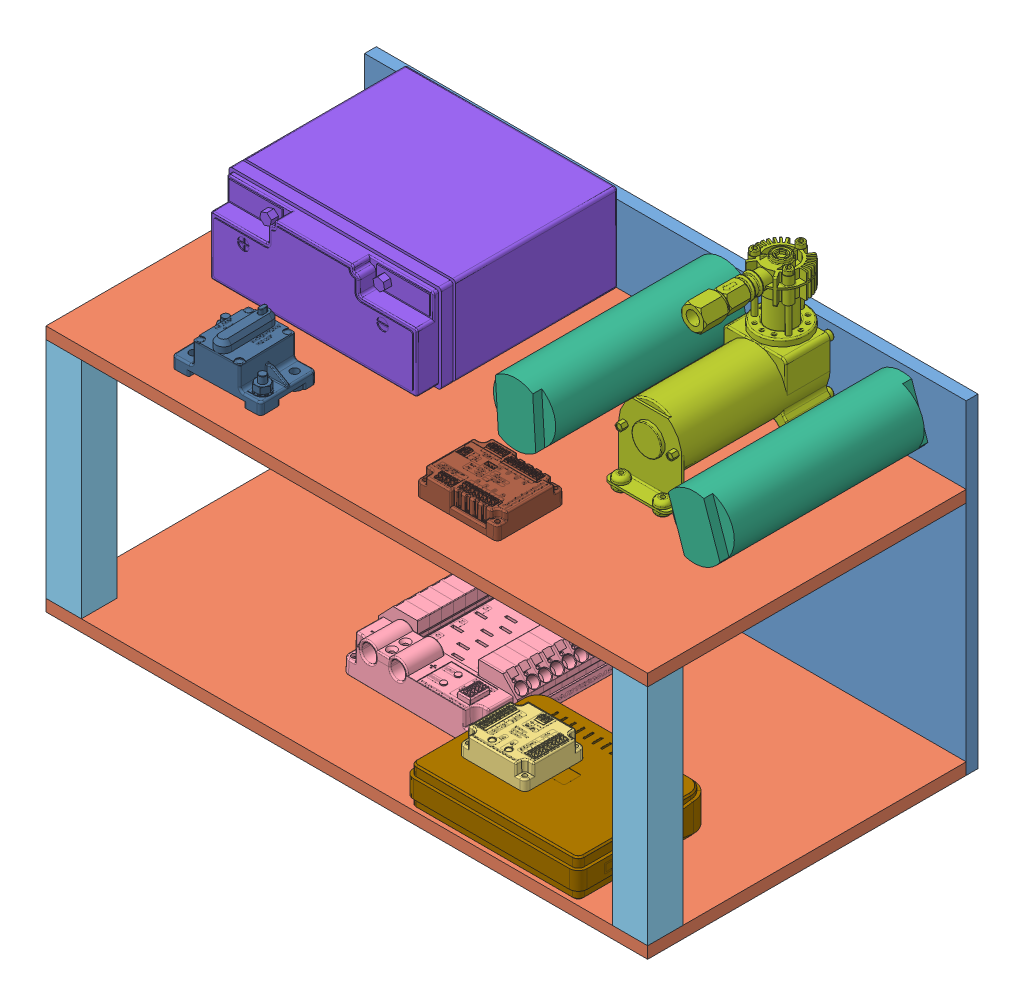
SolidWorks assembly Board Full, configuration Default. Lengths in mm.
Overall size (510 333.82 280.01).
14 component instances, 11 part files, 21 mates.
Components (placement in the parent):
- Wall-1: Wall [Default] at (259.9943 248.2369 361.8956) size (510 275 10)
- Plates-1: Plates [Default] at (259.9943 110.7369 506.8956) size (510 10 270)
- Plates-2: Plates [Default] at (259.9943 310.7369 506.8956) size (510 10 270)
- VRM-1: VRM [Default] at (354.0574 159.5929 589.8618) x (-0.999999 0 -0.001599) z (0.001599 0 -0.999999) size (56.39 27.88 51.56)
- PDP_asmb-1: PDP_asmb [Default] at (243.0238 127.4171 470.0118) x (0.012723 0 -0.999919) z (0.999919 0 0.012723) size (192.68 39.24 124.89)
- Pole-1: Pole [Default] at (19.9943 120.7369 626.8956) size (30 190 30)
- Pole-2: Pole [Default] at (499.9943 120.7369 626.8956) size (30 190 30)
- accumulator-1: accumulator [Default] at (309.232 361.2449 460.0018) x (0.99812 0.061286 0) z (0.061286 -0.99812 0) size (52.83 176.21 52.83)
- accumulator-2: accumulator [Default] at (460.6135 353.791 460.0018) x (-0.945467 -0.325717 0) z (0.325717 -0.945467 0) size (52.83 176.21 52.83)
- User Library-Viair 090 Air Compressor_-1: User Library-Viair 090 Air Compressor_ [Default] at (386.1683 363.2819 422.6956) size (56.72 123.83 152.4)
- User Library-battery 17ahr 12v pb yuasa_-1: User Library-battery 17ahr 12v pb yuasa_ [Default] at (40.1048 320.7369 371.8956) x (1 0 0) z (0 -1 0) size (180 168.8 75)
- Wireless_Bridge-1: Wireless_Bridge [Default] at (382.5626 136.6119 585.4274) size (147.25 32.38 118.55)
- User Library-Circuit Breaker-1_-1: User Library-Circuit Breaker-1_ [Default] at (125.3032 325.5629 594.2924) x (-0.999699 0 0.024553) z (-0.024553 0 -0.999699) size (73.7 42.15 48.27)
- PCM_assmb-1: PCM_assmb [Default] at (320.6025 325.1819 580.9895) size (69.09 27.65 56.9)
Mates (geometry in assembly coordinates):
- Coincident1: coincident anti-aligned: plane of Wall-1 through (259.9943 248.2369 371.8956) normal (0 0 1); plane of Plates-1 through (4.9943 120.7369 371.8956) normal (0 0 -1)
- Coincident2: coincident anti-aligned: line of Wall-1 through (4.9943 110.7369 371.8956) axis (1 0 0); line of Plates-1 through (514.9943 110.7369 371.8956) axis (-1 0 0)
- Coincident4: coincident anti-aligned: line of Wall-1 through (514.9943 110.7369 371.8956) axis (0 1 0); line of Plates-1 through (514.9943 120.7369 371.8956) axis (0 -1 0)
- Coincident7: coincident anti-aligned: plane of Plates-1 through (259.9943 120.7369 506.8956) normal (0 1 0); plane of PDP_asmb-1 through (301.5939 120.7369 378.7254) normal (0 -1 0)
- Coincident8: coincident anti-aligned: plane of Plates-1 through (259.9943 120.7369 506.8956) normal (0 1 0); plane of Pole-1 through (19.9943 120.7369 626.8956) normal (0 -1 0)
- Coincident9: coincident aligned: line of Plates-1 through (4.9943 120.7369 641.8956) axis (1 0 0); line of Pole-1 through (4.9943 120.7369 641.8956) axis (1 0 0)
- Coincident10: coincident aligned: line of Plates-1 through (4.9943 120.7369 371.8956) axis (0 0 1); line of Pole-1 through (4.9943 120.7369 611.8956) axis (0 0 1)
- Coincident11: coincident aligned: line of Plates-1 through (4.9943 120.7369 641.8956) axis (1 0 0); line of Pole-2 through (484.9943 120.7369 641.8956) axis (1 0 0)
- Coincident12: coincident aligned: line of Plates-1 through (514.9943 120.7369 641.8956) axis (0 0 -1); line of Pole-2 through (514.9943 120.7369 641.8956) axis (0 0 -1)
- Coincident18: coincident anti-aligned: plane of Wall-1 through (259.9943 248.2369 371.8956) normal (0 0 1); plane of accumulator-1 through (309.232 361.2449 371.8956) normal (0 0 -1)
- Coincident191: coincident anti-aligned: plane of Wall-1 through (259.9943 248.2369 371.8956) normal (0 0 1); plane of accumulator-2 through (460.6135 353.791 371.8956) normal (0 0 -1)
- Coincident20: coincident anti-aligned: plane of Plates-2 through (259.9943 320.7369 506.8956) normal (0 1 0); circle of User Library-Viair 090 Air Compressor_-1
- Coincident21: coincident anti-aligned: plane of Plates-2 through (259.9943 320.7369 506.8956) normal (0 1 0); plane of User Library-Viair 090 Air Compressor_-1 through (368.8077 320.7369 378.2456) normal (0 -1 0)
- Coincident22: coincident anti-aligned: plane of Wall-1 through (259.9943 248.2369 371.8956) normal (0 0 1); plane of User Library-Viair 090 Air Compressor_-1 through (414.5277 327.7219 371.8956) normal (0 0 -1)
- Coincident23: coincident anti-aligned: plane of Plates-2 through (259.9943 320.7369 506.8956) normal (0 1 0); plane of User Library-battery 17ahr 12v pb yuasa_-1 through (40.1048 320.7369 521.8956) normal (0 -1 0)
- Coincident24: coincident anti-aligned: plane of Wall-1 through (259.9943 248.2369 371.8956) normal (0 0 1); plane of User Library-battery 17ahr 12v pb yuasa_-1 through (40.1048 395.7369 371.8956) normal (0 0 -1)
- Coincident192: coincident anti-aligned: plane of Plates-1 through (259.9943 120.7369 506.8956) normal (0 1 0); plane of Wireless_Bridge-1 through (382.5626 120.7369 585.4274) normal (0 -1 0)
- Coincident193: coincident anti-aligned: plane of VRM-1 through (330.6818 152.4869 609.3717) normal (0 -1 0); plane of Wireless_Bridge-1 through (382.5626 152.4869 585.4274) normal (0 1 0)
- Coincident195: coincident anti-aligned: plane of Plates-2 through (259.9943 320.7369 506.8956) normal (0 1 0); plane of User Library-Circuit Breaker-1_-1 through (155.3163 320.7369 573.1784) normal (0 -1 0)
- Coincident196: coincident anti-aligned: plane of Plates-2 through (259.9943 320.7369 506.8956) normal (0 1 0); plane of User Library-Circuit Breaker-1_-1 through (95.29 320.7369 615.4064) normal (0 -1 0)
- Coincident197: coincident anti-aligned: plane of PCM_assmb-1 through (290.1733 320.7369 556.6817) normal (0 -1 0); plane of Plates-2 through (259.9943 320.7369 506.8956) normal (0 1 0)
